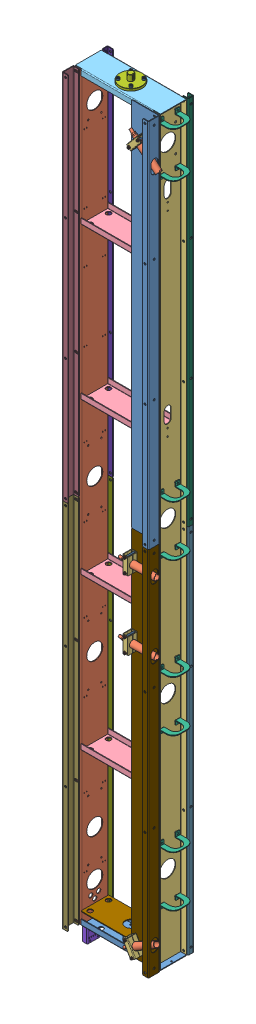
SolidWorks assembly Spray-Pipe Housing Assembly, configuration Default. Lengths in mm.
Overall size (418.83 3349 198).
67 component instances, 21 part files, 85 mates.
Components (placement in the parent):
- spray-pipe housing – base-1: spray-pipe housing – base [Default] at origin size (370 25 120)
- spray-pipe housing – rear panel-1: spray-pipe housing – rear panel [Default] at (0 3 0) x (-1 0 0) z (0 0 -1) size (28 3220 120)
- spray-pipe housing – front panel-1: spray-pipe housing – front panel [Default] at (0 3 0) size (28 3220 120)
- spray-pipe housing – cross bar-1: spray-pipe housing – cross bar [Default] at (0 660.5 0) size (314 25 120)
- spray-pipe housing – cross bar-2: spray-pipe housing – cross bar [Default] at (0 1320.5 0) size (314 25 120)
- spray-pipe housing – cross bar-3: spray-pipe housing – cross bar [Default] at (0 1980.5 0) size (314 25 120)
- spray-pipe housing – cross bar-4: spray-pipe housing – cross bar [Default] at (0 2640.5 0) size (314 25 120)
- spray-pipe housing – cover-1: spray-pipe housing – cover [Default] at (0 3223 0) size (370 25 120)
- spray-pipe housing – pipe clamp-1: spray-pipe housing – pipe clamp [Default] at (194 451.5 0) size (63 20 90)
- spray-pipe housing – pipe clamp-8: spray-pipe housing – pipe clamp [Default] at (194 234.5 0) x (1 0 0) z (0 0 -1) size (63 20 90)
- spray-pipe housing – pipe clamp-9: spray-pipe housing – pipe clamp [Default] at (194 894.5 0) x (1 0 0) z (0 0 -1) size (63 20 90)
- spray-pipe housing – pipe clamp-10: spray-pipe housing – pipe clamp [Default] at (194 1554.5 0) x (1 0 0) z (0 0 -1) size (63 20 90)
- spray-pipe housing – pipe clamp-6: spray-pipe housing – pipe clamp [Default] at (194 1111.5 0) size (63 20 90)
- spray-pipe housing – pipe clamp-7: spray-pipe housing – pipe clamp [Default] at (194 1771.5 0) size (63 20 90)
- spray-pipe housing – pipe clamp-18: spray-pipe housing – pipe clamp [Default] at (194 2982.5 0) x (1 0 0) z (0 0 -1) size (63 20 90)
- spray-pipe housing – pipe clamp-20: spray-pipe housing – pipe clamp [Default] at (194 3175.5 0) size (63 20 90)
- Top flange-1: Top flange [Default] at (0 3226 0) x (0 0 -1) z (1 0 0) size (98 36 98)
- foam-nozzle hose clamp-1: foam-nozzle hose clamp [Default] at (-163 -87 0) x (0 0 1) z (-1 0 0) size (58 120 21)
- spray-pipe housing – main-nozzle locator-1: spray-pipe housing – main-nozzle locator [Default] at (0 53 0) size (314 3 120)
- socket head cap screw_din-1: socket head cap screw_din [DIN 912 M8 x 20 --- 20N] at (28.2843 3244 28.2843) x (0 -1 0) z (0 0 1) size (28 13 13)
- socket head cap screw_din-2: socket head cap screw_din [DIN 912 M8 x 20 --- 20N] at (28.2843 3244 -28.2843) x (0 -1 0) z (0 0 1) size (28 13 13)
- socket head cap screw_din-3: socket head cap screw_din [DIN 912 M8 x 20 --- 20N] at (-28.2843 3244 28.2843) x (0 -1 0) z (0 0 1) size (28 13 13)
- socket head cap screw_din-4: socket head cap screw_din [DIN 912 M8 x 20 --- 20N] at (-28.2843 3244 -28.2843) x (0 -1 0) z (0 0 1) size (28 13 13)
- prevailing torque nut thin insert_din-1: prevailing torque nut thin insert_din [DIN EN ISO 10511 - M8 - N] at (28.2843 3219.3 -28.2843) x (1 0 0) z (0 -1 0) size (13 15.01 6.76)
- prevailing torque nut thin insert_din-2: prevailing torque nut thin insert_din [DIN EN ISO 10511 - M8 - N] at (-28.2843 3219.3 -28.2843) x (1 0 0) z (0 -1 0) size (13 15.01 6.76)
- prevailing torque nut thin insert_din-3: prevailing torque nut thin insert_din [DIN EN ISO 10511 - M8 - N] at (28.2843 3219.3 28.2843) x (1 0 0) z (0 -1 0) size (13 15.01 6.76)
- prevailing torque nut thin insert_din-4: prevailing torque nut thin insert_din [DIN EN ISO 10511 - M8 - N] at (-28.2843 3219.3 28.2843) x (1 0 0) z (0 -1 0) size (13 15.01 6.76)
- rear lower side cover-1: rear lower side cover [Default] at (-188 0 86.5) x (0 0 1) z (-1 0 0) size (50 1613 25)
- rear upper side cover-1: rear upper side cover [Default] at (-188 1613 86.5) x (0 0 1) z (-1 0 0) size (50 1613 25)
- front lower side cover - left-2: front lower side cover - left [Default] at (188 0 -74) x (0 0 1) z (-1 0 0) size (25 1613 25)
- front upper side cover - left-2: front upper side cover - left [Default] at (188 1613 -74) x (0 0 1) z (-1 0 0) size (25 1613 25)
- rear lower side cover - left-2: rear lower side cover - left [Default] at (-188 0 -74) x (0 0 1) z (-1 0 0) size (25 1613 25)
- rear upper side cover - left-2: rear upper side cover - left [Default] at (-188 1613 -74) x (0 0 1) z (-1 0 0) size (25 1613 25)
- front lower side cover-1: front lower side cover [Default] at (188 0 86.5) x (0 0 1) z (-1 0 0) size (50 1613 120)
- front upper side cover-1: front upper side cover [Default] at (188 1613 86.5) x (0 0 1) z (-1 0 0) size (50 1613 120)
- Foam Nozzle Cluster Assembly-1: Foam Nozzle Cluster Assembly [Default] at (56.5958 38.2308 85) x (0.866025 0.5 0) z (0 0 -1) size (162.22 74.5 56)
  - foam nozzle-1: foam nozzle [Default] at origin size (162.22 46 29)
  - foam-nozzle clamp-1: foam-nozzle clamp [Default] at (45.5 -35 -20.5) x (0 1 0) z (1 0 0) size (70 20 25)
  - foam-nozzle clamp-2: foam-nozzle clamp [Default] at (45.5 35 20.5) x (0 -1 0) z (1 0 0) size (70 20 25)
  - socket head cap screw_din-1: socket head cap screw_din [DIN 912 M6 x 50 --- 24N] at (45.5 30 29.5) x (0 0 -1) z (1 0 0) size (56 10 10)
  - socket head cap screw_din-2: socket head cap screw_din [DIN 912 M6 x 50 --- 24N] at (45.5 -30 29.5) x (0 0 -1) z (1 0 0) size (56 10 10)
  - prevailing torque nut thin insert_din-1: prevailing torque nut thin insert_din [DIN EN ISO 10511 - M6 - N] at (45.5 30 -23.4) x (0.923728 0.383049 0) z (0 0 -1) size (10 11.55 6)
  - prevailing torque nut thin insert_din-2: prevailing torque nut thin insert_din [DIN EN ISO 10511 - M6 - N] at (45.5 -30 -23.4) x (0.923728 0.383049 0) z (0 0 -1) size (10 11.55 6)
- Foam Nozzle Cluster Assembly-2: Foam Nozzle Cluster Assembly [Default] at (35.5 1200 85) x (1 0 0) z (0 0 -1) size (162.22 74.5 56)
  - foam nozzle-1: foam nozzle [Default] at origin size (162.22 46 29)
  - foam-nozzle clamp-1: foam-nozzle clamp [Default] at (45.5 -35 -20.5) x (0 1 0) z (1 0 0) size (70 20 25)
  - foam-nozzle clamp-2: foam-nozzle clamp [Default] at (45.5 35 20.5) x (0 -1 0) z (1 0 0) size (70 20 25)
  - socket head cap screw_din-1: socket head cap screw_din [DIN 912 M6 x 50 --- 24N] at (45.5 30 29.5) x (0 0 -1) z (1 0 0) size (56 10 10)
  - socket head cap screw_din-2: socket head cap screw_din [DIN 912 M6 x 50 --- 24N] at (45.5 -30 29.5) x (0 0 -1) z (1 0 0) size (56 10 10)
  - prevailing torque nut thin insert_din-1: prevailing torque nut thin insert_din [DIN EN ISO 10511 - M6 - N] at (45.5 30 -23.4) x (0.923728 0.383049 0) z (0 0 -1) size (10 11.55 6)
  - prevailing torque nut thin insert_din-2: prevailing torque nut thin insert_din [DIN EN ISO 10511 - M6 - N] at (45.5 -30 -23.4) x (0.923728 0.383049 0) z (0 0 -1) size (10 11.55 6)
- Foam Nozzle Cluster Assembly-3: Foam Nozzle Cluster Assembly [Default] at (35.5 1500 85) x (1 0 0) z (0 0 -1) size (162.22 74.5 56)
  - foam nozzle-1: foam nozzle [Default] at origin size (162.22 46 29)
  - foam-nozzle clamp-1: foam-nozzle clamp [Default] at (45.5 -35 -20.5) x (0 1 0) z (1 0 0) size (70 20 25)
  - foam-nozzle clamp-2: foam-nozzle clamp [Default] at (45.5 35 20.5) x (0 -1 0) z (1 0 0) size (70 20 25)
  - socket head cap screw_din-1: socket head cap screw_din [DIN 912 M6 x 50 --- 24N] at (45.5 30 29.5) x (0 0 -1) z (1 0 0) size (56 10 10)
  - socket head cap screw_din-2: socket head cap screw_din [DIN 912 M6 x 50 --- 24N] at (45.5 -30 29.5) x (0 0 -1) z (1 0 0) size (56 10 10)
  - prevailing torque nut thin insert_din-1: prevailing torque nut thin insert_din [DIN EN ISO 10511 - M6 - N] at (45.5 30 -23.4) x (0.923728 0.383049 0) z (0 0 -1) size (10 11.55 6)
  - prevailing torque nut thin insert_din-2: prevailing torque nut thin insert_din [DIN EN ISO 10511 - M6 - N] at (45.5 -30 -23.4) x (0.923728 0.383049 0) z (0 0 -1) size (10 11.55 6)
- Foam Nozzle Cluster Assembly-4: Foam Nozzle Cluster Assembly [Default] at (83.145 3135.2468 85) x (0.766044 -0.642788 0) z (0 0 -1) size (162.22 74.5 56)
  - foam nozzle-1: foam nozzle [Default] at origin size (162.22 46 29)
  - foam-nozzle clamp-1: foam-nozzle clamp [Default] at (45.5 -35 -20.5) x (0 1 0) z (1 0 0) size (70 20 25)
  - foam-nozzle clamp-2: foam-nozzle clamp [Default] at (45.5 35 20.5) x (0 -1 0) z (1 0 0) size (70 20 25)
  - socket head cap screw_din-1: socket head cap screw_din [DIN 912 M6 x 50 --- 24N] at (45.5 30 29.5) x (0 0 -1) z (1 0 0) size (56 10 10)
  - socket head cap screw_din-2: socket head cap screw_din [DIN 912 M6 x 50 --- 24N] at (45.5 -30 29.5) x (0 0 -1) z (1 0 0) size (56 10 10)
  - prevailing torque nut thin insert_din-1: prevailing torque nut thin insert_din [DIN EN ISO 10511 - M6 - N] at (45.5 30 -23.4) x (0.923728 0.383049 0) z (0 0 -1) size (10 11.55 6)
  - prevailing torque nut thin insert_din-2: prevailing torque nut thin insert_din [DIN EN ISO 10511 - M6 - N] at (45.5 -30 -23.4) x (0.923728 0.383049 0) z (0 0 -1) size (10 11.55 6)
Mates (geometry in assembly coordinates):
- Coincident1: coordinate: unknown of hop chua ong phun - chan de-1
- Coincident3: coincident aligned: line of hop chua ong phun - chan de-1 through (141.4229 0 0) axis (0 0 1); line of hop chua ong phun - mat sau-1 through (43.3173 0 3) axis (0 0 1)
- Coincident5: coincident aligned: line of hop chua ong phun - chan de-1 through (141.4229 0 0) axis (0 0 1); line of hop chua ong phun - mat truoc-1 through (43.3173 0 3) axis (0 0 1)
- Coincident6: coincident aligned: plane of hop chua ong phun - chan de-1 through (0 0 0) normal (0 0 1); plane of hop chua ong phun - mat truoc-1 through (0 3 0) normal (0 0 1)
- Coincident7: coincident anti-aligned: plane of hop chua ong phun - chan de-1 through (0 0 0) normal (0 0 1); plane of hop chua ong phun - mat sau-1 through (0 3 0) normal (0 0 -1)
- Coincident8: coincident anti-aligned: plane of hop chua ong phun - chan de-1 through (0 3 0) normal (0 1 0); plane of hop chua ong phun - mat truoc-1 through (161 3 60) normal (0 -1 0)
- Coincident9: coincident anti-aligned: plane of hop chua ong phun - chan de-1 through (0 3 0) normal (0 1 0); plane of hop chua ong phun - mat sau-1 through (-161 3 -60) normal (0 -1 0)
- Coincident10: coincident aligned: line of hop chua ong phun - thanh ngang-1 through (141.4229 0 660.5) axis (0 0 1)
- Coincident11: coincident anti-aligned: plane of hop chua ong phun - mat sau-1 through (0 3 0) normal (0 0 -1); plane of hop chua ong phun - thanh ngang-1 through (0 660.5 0) normal (0 0 1)
- Distance3: distance = 317.5 mm: plane of hop chua ong phun - thanh ngang-1 through (0 660.5 0) normal (0 -1 0); cylinder of hop chua ong phun - mat sau-1 through (-156.999 343 0) axis (-1 0 0) radius 35
- Coincident13: coincident aligned: line of hop chua ong phun - nap-1 through (141.4229 0 3223) axis (0 0 1)
- Coincident14: coincident anti-aligned: plane of hop chua ong phun - mat sau-1 through (0 3 0) normal (0 0 -1); plane of hop chua ong phun - nap-1 through (0 3223 0) normal (0 0 1)
- Coincident15: coincident anti-aligned: plane of hop chua ong phun - mat truoc-1 through (161 3223 -60) normal (0 1 0); plane of hop chua ong phun - nap-1 through (0 3223 0) normal (0 -1 0)
- Concentric2: concentric aligned: cylinder of hop chua ong phun - mat truoc-1 through (156.999 463 -35) axis (1 0 0) radius 4.5; cylinder of hop chua ong phun - kep ong-1 through (165.999 463 -35) axis (1 0 0) radius 3
- Concentric3: concentric aligned: cylinder of hop chua ong phun - mat truoc-1 through (156.999 463 35) axis (1 0 0) radius 4.5; cylinder of hop chua ong phun - kep ong-1 through (165.999 463 35) axis (1 0 0) radius 3
- Concentric8: concentric aligned: cylinder of hop chua ong phun - mat truoc-1 through (156.999 223 -35) axis (1 0 0) radius 4.5; cylinder of hop chua ong phun - kep ong-3 through (165.999 223 -35) axis (1 0 0) radius 3
- Coincident45: coincident aligned: line of mat bich dinh-1 through (50.3092 0 3226) axis (0 0 1)
- Coincident46: coincident anti-aligned: plane of hop chua ong phun - nap-1 through (0 3226 0) normal (0 1 0); plane of mat bich dinh-1 through (0 3226 0) normal (0 -1 0)
- Concentric27: concentric anti-aligned: cylinder of mat bich dinh-1 through (28.2843 3225.999 28.2843) axis (0 1 0) radius 4; cylinder of hop chua ong phun - nap-1 through (28.2843 3226 28.2843) axis (0 -1 0) radius 4
- Coincident52: coincident anti-aligned: plane of hop chua ong phun - mat sau-1 through (-160 3223 -57) normal (-1 0 0); plane of kep dan ong phun bot-1 through (-160 33 -26) normal (1 0 0)
- Coincident53: coincident anti-aligned: plane of hop chua ong phun - mat sau-1 through (0 3 0) normal (0 0 -1); plane of kep dan ong phun bot-1 through (-163 -87 0) normal (0 0 1)
- Coincident54: coincident aligned: line of hop chua ong phun - mat sau-1 through (43.3173 0 3) axis (0 0 1); line of hop chua ong phun - dinh vi ong phun chinh-1 through (141.4229 0 53) axis (0 0 1)
- Distance14: distance = 50 mm anti-aligned: plane of hop chua ong phun - dinh vi ong phun chinh-1 through (0 53 0) normal (0 -1 0); plane of hop chua ong phun - chan de-1 through (0 3 0) normal (0 1 0)
- Concentric40: concentric aligned: cylinder of hop chua ong phun - mat sau-1 through (-156.999 27 0) axis (-1 0 0) radius 3; cylinder of kep dan ong phun bot-1 through (-159.999 27 0) axis (-1 0 0) radius 3
- Concentric41: concentric aligned: cylinder of hop chua ong phun - mat sau-1 through (-156.999 15 -15) axis (-1 0 0) radius 3; cylinder of kep dan ong phun bot-1 through (-159.999 15 -15) axis (-1 0 0) radius 3
- Concentric42: concentric aligned: cylinder of mat bich dinh-1 through (28.2843 3225.999 28.2843) axis (0 1 0) radius 4; cylinder of socket head cap screw_din-1 through (28.2843 3275.75 28.2843) axis (0 1 0) radius 6.5
- Coincident55: coincident anti-aligned: plane of mat bich dinh-1 through (0 3236 49) normal (0 1 0); plane of socket head cap screw_din-1 through (34.7843 3236 28.2843) normal (0 -1 0)
- Concentric43: concentric aligned: cylinder of mat bich dinh-1 through (28.2843 3225.999 -28.2843) axis (0 1 0) radius 4; cylinder of socket head cap screw_din-2 through (28.2843 3275.75 -28.2843) axis (0 1 0) radius 6.5
- Coincident56: coincident anti-aligned: plane of mat bich dinh-1 through (0 3236 49) normal (0 1 0); plane of socket head cap screw_din-2 through (34.7843 3236 -28.2843) normal (0 -1 0)
- Concentric44: concentric aligned: cylinder of mat bich dinh-1 through (-28.2843 3225.999 28.2843) axis (0 1 0) radius 4; cylinder of socket head cap screw_din-3 through (-28.2843 3275.75 28.2843) axis (0 1 0) radius 6.5
- Coincident57: coincident anti-aligned: plane of mat bich dinh-1 through (0 3236 49) normal (0 1 0); plane of socket head cap screw_din-3 through (-21.7843 3236 28.2843) normal (0 -1 0)
- Concentric45: concentric aligned: cylinder of mat bich dinh-1 through (-28.2843 3225.999 -28.2843) axis (0 1 0) radius 4; cylinder of socket head cap screw_din-4 through (-28.2843 3275.75 -28.2843) axis (0 1 0) radius 6.5
- Coincident58: coincident anti-aligned: plane of mat bich dinh-1 through (0 3236 49) normal (0 1 0); plane of socket head cap screw_din-4 through (-21.7843 3236 -28.2843) normal (0 -1 0)
- Concentric46: concentric aligned: cylinder of hop chua ong phun - nap-1 through (28.2843 3226 -28.2843) axis (0 -1 0) radius 4; cylinder of prevailing torque nut thin insert_din-1 through (28.2843 3200.25 -28.2843) axis (0 -1 0) radius 4
- Coincident59: coincident anti-aligned: plane of hop chua ong phun - nap-1 through (0 3223 0) normal (0 -1 0); plane of prevailing torque nut thin insert_din-1 through (28.2843 3223 -20.7787) normal (0 1 0)
- Concentric47: concentric aligned: cylinder of hop chua ong phun - nap-1 through (-28.2843 3226 -28.2843) axis (0 -1 0) radius 4; cylinder of prevailing torque nut thin insert_din-2 through (-28.2843 3200.25 -28.2843) axis (0 -1 0) radius 4
- Coincident60: coincident anti-aligned: plane of hop chua ong phun - nap-1 through (0 3223 0) normal (0 -1 0); plane of prevailing torque nut thin insert_din-2 through (-28.2843 3223 -20.7787) normal (0 1 0)
- Concentric48: concentric aligned: cylinder of hop chua ong phun - nap-1 through (28.2843 3226 28.2843) axis (0 -1 0) radius 4; cylinder of prevailing torque nut thin insert_din-3 through (28.2843 3200.25 28.2843) axis (0 -1 0) radius 4
- Coincident61: coincident anti-aligned: plane of hop chua ong phun - nap-1 through (0 3223 0) normal (0 -1 0); plane of prevailing torque nut thin insert_din-3 through (28.2843 3223 35.7898) normal (0 1 0)
- Concentric49: concentric aligned: cylinder of hop chua ong phun - nap-1 through (-28.2843 3226 28.2843) axis (0 -1 0) radius 4; cylinder of prevailing torque nut thin insert_din-4 through (-28.2843 3200.25 28.2843) axis (0 -1 0) radius 4
- Coincident62: coincident anti-aligned: plane of hop chua ong phun - nap-1 through (0 3223 0) normal (0 -1 0); plane of prevailing torque nut thin insert_din-4 through (-28.2843 3223 35.7898) normal (0 1 0)
- Distance15: distance = 34 mm: cylinder of hop chua ong phun - kep ong-1 through (194 454.5 0) axis (0 -1 0) radius 25; plane of hop chua ong phun - mat truoc-1 through (160 3223 57) normal (1 0 0)
- Distance16: distance = 34 mm: cylinder of hop chua ong phun - kep ong-3 through (194 231.5 0) axis (0 1 0) radius 25; plane of hop chua ong phun - mat truoc-1 through (160 3223 57) normal (1 0 0)
- Distance17: distance = 34 mm: cylinder of hop chua ong phun - kep ong-20 through (194 3178.5 0) axis (0 -1 0) radius 25; plane of hop chua ong phun - mat truoc-1 through (160 3223 57) normal (1 0 0)
- Distance18: distance = 34 mm: cylinder of hop chua ong phun - kep ong-18 through (194 2979.5 0) axis (0 1 0) radius 25; plane of hop chua ong phun - mat truoc-1 through (160 3223 57) normal (1 0 0)
- Concentric52: concentric aligned: cylinder of hop chua ong phun - mat truoc-1 through (156.999 223 35) axis (1 0 0) radius 4.5; cylinder of hop chua ong phun - kep ong-3 through (165.999 223 35) axis (1 0 0) radius 3
- Concentric53: concentric aligned: cylinder of hop chua ong phun - mat truoc-1 through (156.999 3187 35) axis (1 0 0) radius 4.5; cylinder of hop chua ong phun - kep ong-20 through (165.999 3187 35) axis (1 0 0) radius 3
- Concentric56: concentric aligned: cylinder of hop chua ong phun - mat truoc-1 through (156.999 3187 -35) axis (1 0 0) radius 4.5; cylinder of hop chua ong phun - kep ong-20 through (165.999 3187 -35) axis (1 0 0) radius 3
- Concentric57: concentric aligned: cylinder of hop chua ong phun - mat truoc-1 through (156.999 2971 35) axis (1 0 0) radius 4.5; circle of hop chua ong phun - kep ong-18
- Concentric58: concentric aligned: cylinder of hop chua ong phun - mat truoc-1 through (156.999 2971 -35) axis (1 0 0) radius 4.5; cylinder of hop chua ong phun - kep ong-18 through (165.999 2971 -35) axis (1 0 0) radius 3
- Distance26: distance = 1.5 mm anti-aligned: plane of op hong duoi truoc_v3-1 through (188 1613 61.5) normal (0 0 -1); plane of hop chua ong phun - mat truoc-1 through (160 3223 60) normal (0 0 1)
- Coincident129: coincident aligned: plane of hop chua ong phun - chan de-1 through (0 0 0) normal (0 -1 0); plane of op hong duoi truoc_v3-1 through (183.5 0 108.5) normal (0 -1 0)
- Distance27: distance = 3 mm aligned: plane of op hong duoi truoc_v3-1 through (188 1613 61.5) normal (1 0 0); plane of hop chua ong phun - mat truoc-1 through (185 3223 57) normal (1 0 0)
- Distance28: distance = 1.5 mm anti-aligned: plane of op hong tren truoc_v3-1 through (188 3226 61.5) normal (0 0 -1); plane of hop chua ong phun - mat truoc-1 through (160 3223 60) normal (0 0 1)
- Coincident132: coincident aligned: plane of op hong duoi truoc_v3-1 through (188 1613 61.5) normal (1 0 0); plane of op hong tren truoc_v3-1 through (188 3226 61.5) normal (1 0 0)
- Coincident133: coincident: line of op hong duoi truoc_v3-1 through (188 1613 107) axis (0 0 -1); plane of op hong tren truoc_v3-1 through (183.5 1613 108.5) normal (0 -1 0)
- Distance31: distance = 1.5 mm anti-aligned: plane of hop chua ong phun - mat sau-1 through (-160 3223 60) normal (0 0 1); plane of op hong duoi sau-1 through (-188 1613 61.5) normal (0 0 -1)
- Distance29: distance = 6 mm aligned: plane of op hong duoi sau-1 through (-163 1613 61.5) normal (1 0 0); plane of hop chua ong phun - mat sau-1 through (-157 3223 -57) normal (1 0 0)
- Distance30: distance = 1.5 mm anti-aligned: plane of op hong tren sau-1 through (-188 3226 61.5) normal (0 0 -1); plane of hop chua ong phun - mat sau-1 through (-160 3223 60) normal (0 0 1)
- Coincident144: coincident anti-aligned: plane of op hong duoi sau-1 through (-185 1613 66) normal (0 1 0); plane of op hong tren sau-1 through (-185 1613 107) normal (0 -1 0)
- Coincident145: coincident aligned: plane of op hong duoi sau-1 through (-188 1613 61.5) normal (-1 0 0); plane of op hong tren sau-1 through (-188 3226 61.5) normal (-1 0 0)
- Distance37: distance = 1.5 mm anti-aligned: plane of hop chua ong phun - mat sau-1 through (-160 3223 -60) normal (0 0 -1); plane of op hong duoi sau - trai-2 through (-188 1613 -61.5) normal (0 0 1)
- Coincident156: coincident aligned: plane of hop chua ong phun - chan de-1 through (0 0 0) normal (0 -1 0); plane of op hong duoi sau - trai-2 through (-183.5 0 -83.5) normal (0 -1 0)
- Coincident157: coincident aligned: plane of op hong duoi sau-1 through (-188 1613 61.5) normal (-1 0 0); plane of op hong duoi sau - trai-2 through (-188 1613 -86.5) normal (-1 0 0)
- Coincident158: coincident aligned: plane of op hong duoi sau - trai-2 through (-188 1613 -86.5) normal (-1 0 0); plane of op hong tren sau - trai-2 through (-188 3226 -86.5) normal (-1 0 0)
- Coincident159: coincident anti-aligned: plane of op hong duoi sau - trai-2 through (-183.5 1613 -64.5) normal (0 1 0); plane of op hong tren sau - trai-2 through (-183.5 1613 -83.5) normal (0 -1 0)
- Coincident160: coincident aligned: plane of op hong duoi sau - trai-2 through (-188 1613 -86.5) normal (0 0 -1); plane of op hong tren sau - trai-2 through (-188 3226 -86.5) normal (0 0 -1)
- Coincident161: coincident anti-aligned: plane of op hong duoi truoc_v3-1 through (188 1613 64.5) normal (0 0 1); plane of rap cum bec phun bot-1/kep bec phun bot-2 through (89.3253 97.5417 64.5) normal (0 0 -1)
- Concentric83: concentric aligned: cylinder of op hong duoi truoc_v3-1 through (81 86.9615 111.501) axis (0 0 -1) radius 3.25; cylinder of rap cum bec phun bot-1/socket head cap screw_din-2 through (81 86.9615 23.75) axis (0 0 -1) radius 3
- Concentric84: concentric aligned: cylinder of op hong duoi truoc_v3-1 through (111 35 111.501) axis (0 0 -1) radius 3.25; cylinder of rap cum bec phun bot-1/socket head cap screw_din-1 through (111 35 23.75) axis (0 0 -1) radius 3
- Coincident162: coincident anti-aligned: plane of op hong duoi truoc_v3-1 through (188 1613 64.5) normal (0 0 1); plane of rap cum bec phun bot-2/kep bec phun bot-2 through (93.5 1235 64.5) normal (0 0 -1)
- Concentric85: concentric aligned: cylinder of op hong duoi truoc_v3-1 through (81 1230 111.501) axis (0 0 -1) radius 3.25; cylinder of rap cum bec phun bot-2/socket head cap screw_din-2 through (81 1230 23.75) axis (0 0 -1) radius 3
- Concentric86: concentric aligned: cylinder of op hong duoi truoc_v3-1 through (81 1170 111.501) axis (0 0 -1) radius 3.25; cylinder of rap cum bec phun bot-2/socket head cap screw_din-1 through (81 1170 23.75) axis (0 0 -1) radius 3
- Coincident163: coincident anti-aligned: plane of op hong duoi truoc_v3-1 through (188 1613 64.5) normal (0 0 1); plane of rap cum bec phun bot-3/kep bec phun bot-2 through (93.5 1535 64.5) normal (0 0 -1)
- Concentric87: concentric aligned: cylinder of op hong duoi truoc_v3-1 through (81 1530 111.501) axis (0 0 -1) radius 3.25; cylinder of rap cum bec phun bot-3/socket head cap screw_din-2 through (81 1530 23.75) axis (0 0 -1) radius 3
- Concentric88: concentric aligned: cylinder of op hong duoi truoc_v3-1 through (81 1470 111.501) axis (0 0 -1) radius 3.25; cylinder of rap cum bec phun bot-3/socket head cap screw_din-1 through (81 1470 23.75) axis (0 0 -1) radius 3
- Coincident164: coincident anti-aligned: plane of op hong duoi truoc_v3-1 through (188 1613 64.5) normal (0 0 1); plane of rap cum bec phun bot-4/kep bec phun bot-2 through (150.0731 3124.7767 64.5) normal (0 0 -1)
- Concentric89: concentric aligned: cylinder of op hong tren truoc_v3-1 through (137.2836 3128.9813 111.501) axis (0 0 -1) radius 3.25; cylinder of rap cum bec phun bot-4/socket head cap screw_din-2 through (137.2836 3128.9813 23.75) axis (0 0 -1) radius 3
- Concentric90: concentric aligned: cylinder of op hong tren truoc_v3-1 through (98.7164 3083.0187 111.501) axis (0 0 -1) radius 3.25; cylinder of rap cum bec phun bot-4/socket head cap screw_din-1 through (98.7164 3083.0187 23.75) axis (0 0 -1) radius 3
- Coincident166: coincident aligned: plane of hop chua ong phun - chan de-1 through (0 0 0) normal (0 -1 0); plane of op hong duoi truoc - trai-2 through (183.5 0 -64.5) normal (0 -1 0)
- Distance35: distance = 1.5 mm anti-aligned: plane of op hong duoi truoc - trai-2 through (188 1613 -61.5) normal (0 0 1); plane of hop chua ong phun - mat truoc-1 through (160 3223 -60) normal (0 0 -1)
- Coincident169: coincident aligned: plane of op hong duoi truoc - trai-2 through (188 1613 -86.5) normal (1 0 0); plane of op hong duoi truoc_v3-1 through (188 1613 61.5) normal (1 0 0)
- Coincident170: coincident anti-aligned: plane of op hong duoi truoc - trai-2 through (183.5 1613 -83.5) normal (0 1 0); plane of op hong tren truoc - trai-2 through (183.5 1613 -64.5) normal (0 -1 0)
- Coincident171: coincident aligned: plane of op hong duoi truoc - trai-2 through (188 1613 -86.5) normal (1 0 0); plane of op hong tren truoc - trai-2 through (188 3226 -86.5) normal (1 0 0)
- Coincident172: coincident aligned: plane of op hong duoi truoc - trai-2 through (188 1613 -86.5) normal (0 0 -1); plane of op hong tren truoc - trai-2 through (188 3226 -86.5) normal (0 0 -1)
